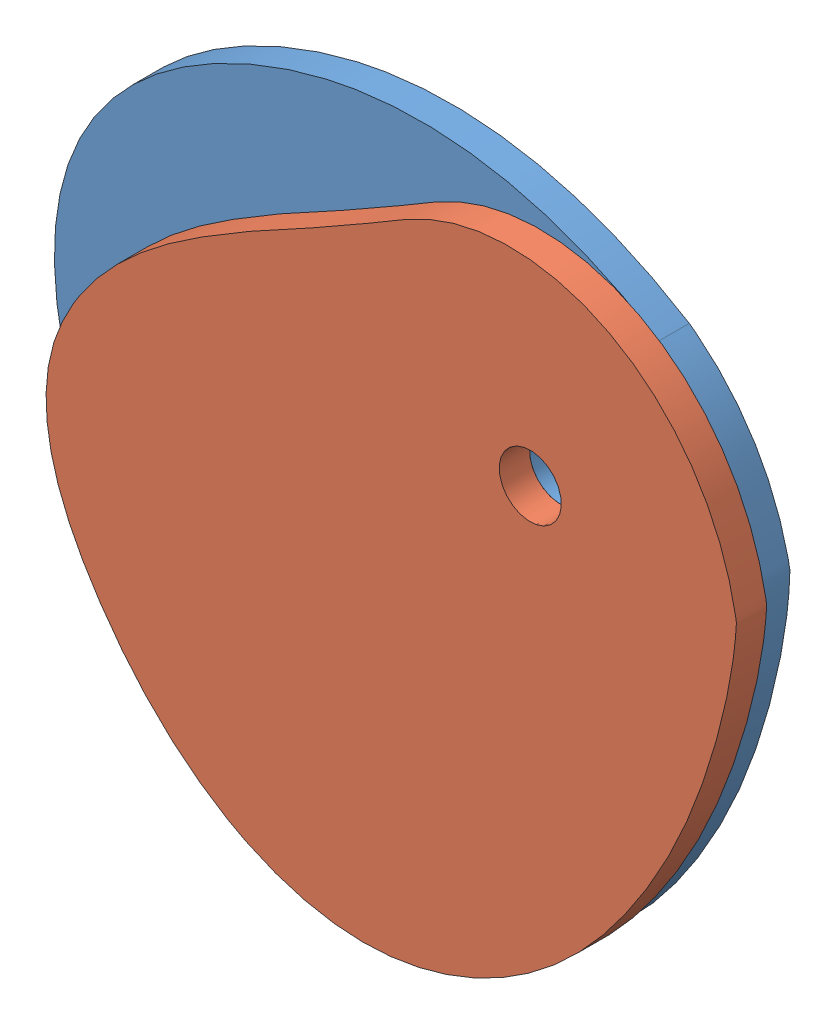
SolidWorks assembly assembly-check-2023-08-09, configuration Default. Lengths in mm.
Overall size (78.1 75.79 6).
2 component instances, 2 part files, 2 mates.
Components (placement in the parent):
- inner_cam_profile_2023-08-09-1: inner_cam_profile_2023-08-09 [Default] at (26.8342 23.6645 -13.4422) size (76 72.84 3)
- inner_cam_profile-1: inner_cam_profile [Default] at (26.8342 23.6645 -10.4422) x (0.997385 -0.072267 0) z (0 0 1) size (67.2 67.93 3)
Mates (geometry in assembly coordinates):
- Coincident1: coincident anti-aligned: plane of inner_cam_profile_2023-08-09-1 through (29.6643 -15.437 -11.9422) normal (0 0 1); plane of inner_cam_profile-1 through (-19.4069 -0.9998 -11.9422) normal (0 0 -1)
- Concentric1: concentric aligned: cylinder of inner_cam_profile_2023-08-09-1 through (26.8342 23.6645 -11.9422) axis (0 0 -1) radius 3.075; cylinder of inner_cam_profile-1 through (26.8342 23.6645 -8.9422) axis (0 0 -1) radius 3.075
